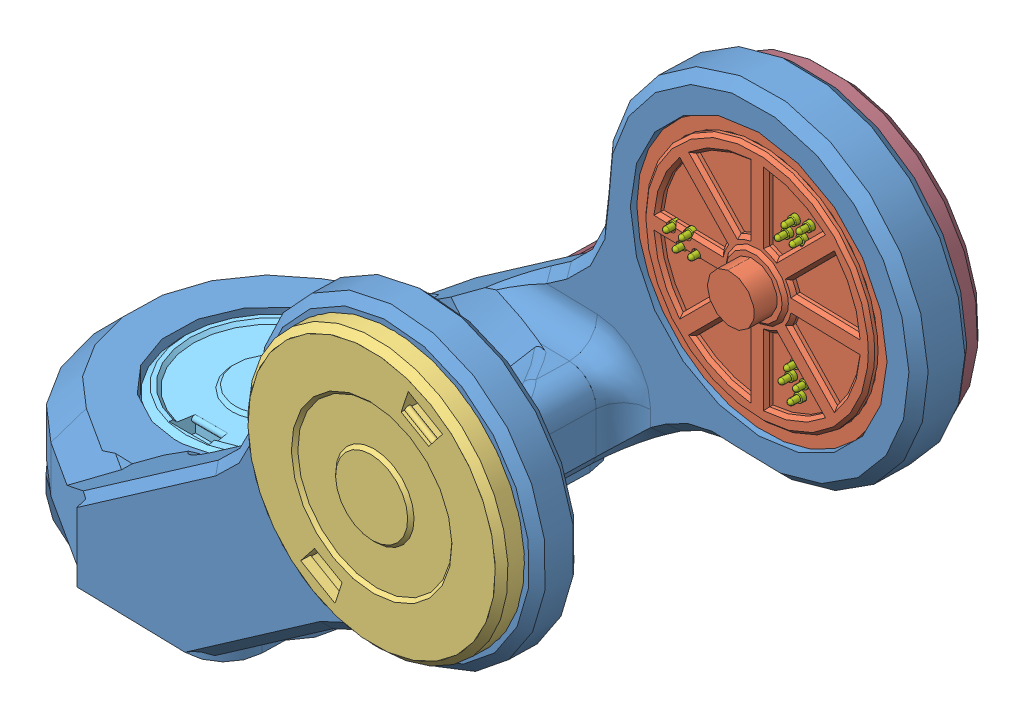
SolidWorks assembly fork_assembly_211201, configuration По умолчанию. Lengths in mm.
Overall size (216.2 166.88 147.03).
40 component instances, 13 part files, 37 mates.
Components (placement in the parent):
- main_fork_211124-1: main_fork_211124 [По умолчанию] at (-30.0243 -35 2.0927) x (0.99973 0 0.023253) z (-0.023253 0 0.99973) size (205.5 159 128)
- fixing_cup_211126-1: fixing_cup_211126 [По умолчанию] at (-28.7106 -35 -54.392) x (0.99973 0 0.023253) z (-0.023253 0 0.99973) size (90 90 26.5)
- fork_fixing_crew_211126-1: fork_fixing_crew_211126 [По умолчанию] at (-31.3381 -35 58.5774) x (0.878636 -0.477054 0.020436) z (-0.476925 -0.878874 -0.011093) size (83 13.97 83)
- fixing_ring_211126-2: fixing_ring_211126 [По умолчанию] at (-28.7106 -35 -54.392) x (0.922257 0.385983 0.021451) z (0.023253 0 -0.99973) size (90 90 5.02)
- main_fork_fixing_211201-1: main_fork_fixing_211201 [По умолчанию] at (-134.4961 -139 -0.3372) size (58 48 58)
- asm_contact_brd_211214-1: asm_contact_brd_211214 [По умолчанию] at (-28.7106 -35 -54.392) x (-0.573421 0.819152 -0.013337) z (-0.818931 -0.573576 -0.019047) size (65 12.3 65)
  - contact_brd3_211213-1: contact_brd3_211213 [По умолчанию] at origin size (65 1.5 65)
  - pogopin_a734_3_3x12_211214-5: pogopin_a734_3_3x12_211214 [По умолчанию] at (-24.5 -10.8 0) x (-0.957911 0 -0.287064) z (0 -1 0) size (3.3 3.3 12)
  - pogopin_a734_3_3x12_211214-6: pogopin_a734_3_3x12_211214 [По умолчанию] at (-19.5 -10.8 0) x (-0.957911 0 -0.287064) z (0 -1 0) size (3.3 3.3 12)
  - pogopin_a734_3_3x12_211214-7: pogopin_a734_3_3x12_211214 [По умолчанию] at (-27.2075 -10.8 4) x (-0.957911 0 -0.287064) z (0 -1 0) size (3.3 3.3 12)
  - pogopin_a734_3_3x12_211214-8: pogopin_a734_3_3x12_211214 [По умолчанию] at (-22.1416 -10.8 4) x (-0.957911 0 -0.287064) z (0 -1 0) size (3.3 3.3 12)
  - pogopin_a734_3_3x12_211214-9: pogopin_a734_3_3x12_211214 [По умолчанию] at (17.0679 -10.8 21.5624) x (0.230351 0 0.973108) z (0 -1 0) size (3.3 3.3 12)
  - pogopin_a734_3_3x12_211214-10: pogopin_a734_3_3x12_211214 [По умолчанию] at (10.1397 -10.8 -25.5624) x (0.72756 0 -0.686044) z (0 -1 0) size (3.3 3.3 12)
  - pogopin_a734_3_3x12_211214-11: pogopin_a734_3_3x12_211214 [По умолчанию] at (14.5349 -10.8 17.1752) x (0.230351 0 0.973108) z (0 -1 0) size (3.3 3.3 12)
  - pogopin_a734_3_3x12_211214-12: pogopin_a734_3_3x12_211214 [По умолчанию] at (7.6067 -10.8 -21.1752) x (0.72756 0 -0.686044) z (0 -1 0) size (3.3 3.3 12)
  - pogopin_a734_3_3x12_211214-13: pogopin_a734_3_3x12_211214 [По умолчанию] at (12.25 -10.8 21.2176) x (0.230351 0 0.973108) z (0 -1 0) size (3.3 3.3 12)
  - pogopin_a734_3_3x12_211214-14: pogopin_a734_3_3x12_211214 [По умолчанию] at (12.25 -10.8 -21.2176) x (0.72756 0 -0.686044) z (0 -1 0) size (3.3 3.3 12)
  - pogopin_a734_3_3x12_211214-15: pogopin_a734_3_3x12_211214 [По умолчанию] at (9.75 -10.8 16.8875) x (0.230351 0 0.973108) z (0 -1 0) size (3.3 3.3 12)
  - pogopin_a734_3_3x12_211214-16: pogopin_a734_3_3x12_211214 [По умолчанию] at (9.75 -10.8 -16.8875) x (0.72756 0 -0.686044) z (0 -1 0) size (3.3 3.3 12)
- asm_contact_brd4_211214-1: asm_contact_brd4_211214 [По умолчанию] at (-134.4961 -114.5 -0.3372) x (-0.99973 0 -0.023253) z (0.023253 0 -0.99973) size (92 17.38 113.16)
  - contact_brd4_211213-1: contact_brd4_211213 [По умолчанию] at origin size (92 1.5 105)
  - pogopin_a734_3_3x12_211214-1: pogopin_a734_3_3x12_211214 [По умолчанию] at (39.5125 -10.8 18.1937) x (0.802221 0 0.597027) z (0 -1 0) size (3.3 3.3 12)
  - pogopin_a734_3_3x12_211214-2: pogopin_a734_3_3x12_211214 [По умолчанию] at (35.0753 -10.8 20.2507) x (0.802221 0 0.597027) z (0 -1 0) size (3.3 3.3 12)
  - pogopin_a734_3_3x12_211214-3: pogopin_a734_3_3x12_211214 [По умолчанию] at (35.1615 -10.8 15.6817) x (0.802221 0 0.597027) z (0 -1 0) size (3.3 3.3 12)
  - pogopin_a734_3_3x12_211214-4: pogopin_a734_3_3x12_211214 [По умолчанию] at (30.7439 -10.8 17.75) x (0.802221 0 0.597027) z (0 -1 0) size (3.3 3.3 12)
  - pogopin_a734_3_3x12_211214-5: pogopin_a734_3_3x12_211214 [По умолчанию] at (-4 -10.8 -38.2916) x (0.802221 0 0.597027) z (0 -1 0) size (3.3 3.3 12)
  - pogopin_a734_3_3x12_211214-6: pogopin_a734_3_3x12_211214 [По умолчанию] at (-4 -10.8 -43.3157) x (0.802221 0 0.597027) z (0 -1 0) size (3.3 3.3 12)
  - pogopin_a734_3_3x12_211214-7: pogopin_a734_3_3x12_211214 [По умолчанию] at (0 -10.8 -40.5014) x (0.802221 0 0.597027) z (0 -1 0) size (3.3 3.3 12)
  - pogopin_a734_3_3x12_211214-8: pogopin_a734_3_3x12_211214 [По умолчанию] at (0 -10.8 -35.5) x (0.802221 0 0.597027) z (0 -1 0) size (3.3 3.3 12)
  - pogopin_a734_3_3x12_211214-9: pogopin_a734_3_3x12_211214 [По умолчанию] at (-31.1615 -10.8 22.6099) x (0.802221 0 0.597027) z (0 -1 0) size (3.3 3.3 12)
  - pogopin_a734_3_3x12_211214-10: pogopin_a734_3_3x12_211214 [По умолчанию] at (-35.5125 -10.8 25.122) x (0.802221 0 0.597027) z (0 -1 0) size (3.3 3.3 12)
  - pogopin_a734_3_3x12_211214-11: pogopin_a734_3_3x12_211214 [По умолчанию] at (-35.0753 -10.8 20.2507) x (0.802221 0 0.597027) z (0 -1 0) size (3.3 3.3 12)
  - pogopin_a734_3_3x12_211214-12: pogopin_a734_3_3x12_211214 [По умолчанию] at (-30.7439 -10.8 17.75) x (0.802221 0 0.597027) z (0 -1 0) size (3.3 3.3 12)
  - pld_8r_211215-1: pld_8r_211215 [По умолчанию] at (-2.417 -2.49 55.73) x (1 0 0) z (0 1 0) size (10.16 13.05 9.07)
- fork_board_fixer_211215-1: fork_board_fixer_211215 [По умолчанию] at (-134.4961 -123.5 -0.3372) x (0.99973 0 0.023253) z (-0.023253 0 0.99973) size (100 9 100)
- asm_com__211215-1: asm_com__211215 [По умолчанию] at (-90.4113 -78.5035 -69.8906) x (-0.573421 0.819152 -0.013337) z (0.818931 0.573576 0.019047) size (12.74 9.6 112.44)
  - conect_brd2_211214-1: conect_brd2_211214 [По умолчанию] at origin size (12.74 1.5 112.44)
  - pbd_8_211215-1: pbd_8_211215 [По умолчанию] at (0.133 -1.8298 56.5764) x (1 0 0) z (0 0 -1) size (10.23 9.1 5.08)
  - pbd_8_211215-2: pbd_8_211215 [По умолчанию] at (3.4585 -1.8298 -49.3785) x (0.587785 0 -0.809017) z (-0.809017 0 -0.587785) size (10.23 9.1 5.08)
- main_cap_211215-2: main_cap_211215 [По умолчанию] at (-28.5013 -35 -63.3896) x (-0.999729 -0.000909 -0.023252) z (0.000909 -1 0.000021) size (165.73 23 131)
Mates (geometry in assembly coordinates):
- Концентричный8: concentric anti-aligned: cylinder of main_fork_211124-1 through (-28.5943 -35 -59.3906) axis (-0.023253 0 0.99973) radius 46; cylinder of fork_fixing_crew_211126-1 through (-31.6404 -35 71.5739) axis (0.023253 0 -0.99973) radius 41.5
- Расстояние1: distance = 4 mm anti-aligned: plane of fork_fixing_crew_211126-1 through (-31.5706 -35 68.5747) normal (0.023253 0 -0.99973); plane of main_fork_211124-1 through (-31.4776 -35 64.5758) normal (-0.023253 0 0.99973)
- Совпадение13: coincident anti-aligned: plane of fixing_cup_211126-1 through (-28.7106 -35 -54.392) normal (0.023253 0 -0.99973); plane of fixing_ring_211126-2 through (-28.7106 -35 -54.392) normal (-0.023253 0 0.99973)
- Концентричный9: concentric aligned: cylinder of main_fork_211124-1 through (-29.1524 -35 -35.3971) axis (0.023253 0 -0.99973) radius 41; cylinder of fixing_cup_211126-1 through (-28.8617 -35 -47.8938) axis (0.023253 0 -0.99973) radius 40.5
- Совпадение15: coincident anti-aligned: plane of main_fork_211124-1 through (-43.888 7.2862 -63.7474) normal (0.939439 0.34202 0.02185); plane of fixing_cup_211126-1 through (-28.8617 -35 -47.8938) normal (-0.939439 -0.34202 -0.02185)
- Концентричный10: concentric aligned: cylinder of main_fork_211124-1 through (-28.5013 -35 -63.3896) axis (-0.023253 0 0.99973) radius 45; cylinder of fixing_ring_211126-2 through (-28.6059 -35 -58.8908) axis (-0.023253 0 0.99973) radius 45
- Совпадение21: coincident anti-aligned: plane of main_fork_211124-1 through (-134.4961 -99 -0.3372) normal (0 1 0); plane of main_fork_fixing_211201-1 through (-134.4961 -99 -0.3372) normal (0 -1 0)
- Концентричный13: concentric aligned: cylinder of main_fork_211124-1 through (-134.4961 -59 -0.3372) axis (0 -1 0) radius 30; cylinder of main_fork_fixing_211201-1 through (-134.4961 -92 -0.3372) axis (0 -1 0) radius 29
- Концентричный16: concentric anti-aligned: cylinder of main_fork_211124-1 through (-134.4961 -92 -0.3372) axis (0 1 0) radius 45.1398; cylinder of contact_brd4_211213-1 through (-134.4961 -90.5 -0.3372) axis (0 -1 0) radius 46
- Совпадение23: coincident anti-aligned: plane of main_fork_211124-1 through (-134.4961 -92 -0.3372) normal (0 1 0); plane of contact_brd4_211213-1 through (-134.4961 -92 -0.3372) normal (0 -1 0)
- Концентричный17: concentric aligned: cylinder of fixing_cup_211126-1 through (-56.5394 -33.3865 -38.5348) axis (0.023253 0 -0.99973) radius 1.45; cylinder of asm_contact_brd_211214-1/pogopin_a734_3_3x12_211214-1 through (-54.3652 -33.3865 -132.0165) axis (0.023253 0 -0.99973) radius 1.35
- Концентричный18: concentric aligned: cylinder of fixing_cup_211126-1 through (-16.7686 -59.5814 -37.6098) axis (0.023253 0 -0.99973) radius 1.45; cylinder of asm_contact_brd_211214-1/pogopin_a734_3_3x12_211214-7 through (-16.357 -59.5814 -55.305) axis (0.023253 0 -0.99973) radius 1.35
- Концентричный19: concentric aligned: cylinder of fixing_cup_211126-1 through (-17.9125 -50.9735 -37.6364) axis (0.023253 0 -0.99973) radius 1.45; cylinder of asm_contact_brd_211214-1/pogopin_a734_3_3x12_211214-6 through (-17.5009 -50.9735 -55.3316) axis (0.023253 0 -0.99973) radius 1.35
- Совпадение26: coincident anti-aligned: plane of main_fork_211124-1 through (-28.8268 -35 -49.3933) normal (0.023253 0 -0.99973); plane of fixing_cup_211126-1 through (-28.8268 -35 -49.3933) normal (-0.023253 0 0.99973)
- Концентричный20: concentric aligned: cylinder of asm_contact_brd_211214-1/contact_brd3_211213-1 through (-52.9436 -47.4055 -56.456) axis (-0.023253 0 0.99973) radius 0.5; cylinder of conect_brd_211213-1 through (-52.6529 -47.4055 -68.9527) axis (-0.023253 0 0.99973) radius 0.5
- Концентричный21: concentric aligned: cylinder of asm_contact_brd_211214-1/contact_brd3_211213-1 through (-50.8635 -45.9486 -56.4077) axis (-0.023253 0 0.99973) radius 0.5; cylinder of conect_brd_211213-1 through (-50.5729 -45.9486 -68.9043) axis (-0.023253 0 0.99973) radius 0.5
- Расстояние2: distance = 10 mm anti-aligned: plane of asm_contact_brd_211214-1/contact_brd3_211213-1 through (-28.6757 -35 -55.8916) normal (0.023253 0 -0.99973); plane of conect_brd_211213-1 through (-90.1885 -78.322 -68.3253) normal (-0.023253 0 0.99973)
- Концентричный22: concentric anti-aligned: cylinder of asm_contact_brd_211214-1/contact_brd3_211213-1 through (-50.8635 -45.9486 -56.4077) axis (-0.023253 0 0.99973) radius 0.5; cylinder of conect_brd2_211214-1 through (-50.6077 -45.9486 -67.4047) axis (0.023253 0 -0.99973) radius 0.5
- Концентричный23: concentric anti-aligned: cylinder of asm_contact_brd_211214-1/contact_brd3_211213-1 through (-46.494 -52.1906 -56.306) axis (-0.023253 0 0.99973) radius 0.5; cylinder of conect_brd2_211214-1 through (-46.2383 -52.1906 -67.3031) axis (0.023253 0 -0.99973) radius 0.5
- Расстояние3: distance = 10 mm anti-aligned: plane of asm_contact_brd_211214-1/contact_brd3_211213-1 through (-28.6757 -35 -55.8916) normal (0.023253 0 -0.99973); plane of conect_brd2_211214-1 through (-90.4476 -78.5035 -68.3313) normal (-0.023253 0 0.99973)
- Параллельность4: parallel anti-aligned: plane of contact_brd4_211213-1 through (-129.939 -90.5 -67.2493) normal (0.023253 0 -0.99973); plane of conect_brd2_211214-1 through (-90.4476 -78.5035 -68.3313) normal (-0.023253 0 0.99973)
- Параллельность5: parallel anti-aligned: plane of conect_brd2_211214-1 through (-90.4476 -78.5035 -68.3313) normal (-0.023253 0 0.99973); plane of asm_contact_brd4_211214-1/contact_brd4_211213-1 through (-127.1258 -113 -59.1817) normal (0.023253 0 -0.99973)
- Концентричный25: concentric aligned: cylinder of asm_contact_brd4_211214-1/pogopin_a734_3_3x12_211214-12 through (-103.3478 -113.3 -17.3675) axis (0 1 0) radius 1.35; cylinder of fork_board_fixer_211215-1 through (-103.3478 -123.5 -17.3675) axis (0 1 0) radius 1.4
- Концентричный26: concentric aligned: cylinder of asm_contact_brd4_211214-1/pogopin_a734_3_3x12_211214-1 through (-173.5748 -113.3 -19.4448) axis (0 1 0) radius 1.35; cylinder of fork_board_fixer_211215-1 through (-173.5748 -123.5 -19.4448) axis (0 1 0) radius 1.4
- Концентричный28: concentric anti-aligned: cylinder of main_fork_211124-1 through (-134.4961 -125.5 -0.3372) axis (0 1 0) radius 33; cylinder of asm_contact_brd4_211214-1/contact_brd4_211213-1 through (-134.4961 -113 -0.3372) axis (0 -1 0) radius 46
- Совпадение33: coincident anti-aligned: plane of main_fork_211124-1 through (-134.4961 -113 -0.3372) normal (0 -1 0); plane of asm_contact_brd4_211214-1/contact_brd4_211213-1 through (-134.4961 -113 -0.3372) normal (0 1 0)
- Совпадение35: coincident anti-aligned: plane of main_fork_211124-1 through (-134.4961 -114.5 -0.3372) normal (0 -1 0); plane of fork_board_fixer_211215-1 through (-134.4961 -114.5 -0.3372) normal (0 1 0)
- Совпадение36: coincident anti-aligned: plane of fixing_cup_211126-1 through (-28.7106 -35 -54.392) normal (0.023253 0 -0.99973); plane of asm_contact_brd_211214-1/contact_brd3_211213-1 through (-28.7106 -35 -54.392) normal (-0.023253 0 0.99973)
- Совпадение37: coincident anti-aligned: plane of conect_brd2_211214-1 through (-90.4476 -78.5035 -68.3313) normal (-0.023253 0 0.99973); plane of pbd_8_211215-1 through (-132.7356 -116.99 -69.3149) normal (0.023253 0 -0.99973)
- Совпадение38: coincident aligned: plane of asm_contact_brd4_211214-1/pld_8r_211215-1 through (-138.203 -113 -58.999) normal (-0.99973 0 -0.023253); plane of pbd_8_211215-1 through (-138.1463 -113 -61.4386) normal (-0.99973 0 -0.023253)
- Совпадение39: coincident aligned: plane of asm_contact_brd4_211214-1/pld_8r_211215-1 through (-138.203 -107.92 -58.999) normal (0 1 0); plane of pbd_8_211215-1 through (-138.1463 -107.92 -61.4386) normal (0 1 0)
- Концентричный29: concentric anti-aligned: cylinder of asm_contact_brd_211214-1/contact_brd3_211213-1 through (-50.8635 -45.9486 -56.4077) axis (-0.023253 0 0.99973) radius 0.5; cylinder of asm_com__211215-1/conect_brd2_211214-1 through (-50.6064 -45.9486 -67.4644) axis (0.023253 0 -0.99973) radius 0.5
- Концентричный30: concentric anti-aligned: cylinder of asm_contact_brd_211214-1/contact_brd3_211213-1 through (-52.9436 -47.4055 -56.456) axis (-0.023253 0 0.99973) radius 0.5; cylinder of asm_com__211215-1/conect_brd2_211214-1 through (-52.6864 -47.4055 -67.5128) axis (0.023253 0 -0.99973) radius 0.5
- Совпадение40: coincident anti-aligned: plane of asm_contact_brd4_211214-1/pld_8r_211215-1 through (-130.66 -116.99 -61.3242) normal (0.023253 0 -0.99973); plane of asm_com__211215-1/pbd_8_211215-2 through (-133.053 -103.9928 -61.3799) normal (-0.023253 0 0.99973)
- Совпадение43: coincident anti-aligned: plane of main_fork_211124-1 through (-28.5013 -35 -63.3896) normal (0.023253 0 -0.99973); plane of main_cap_211215-2 through (-28.5013 -35 -63.3896) normal (-0.023253 0 0.99973)
- Концентричный32: concentric aligned: cylinder of fixing_cup_211126-1 through (-28.478 -35 -64.3893) axis (-0.023253 0 0.99973) radius 16.85; cylinder of main_cap_211215-2 through (-28.3618 -35 -69.3879) axis (-0.023253 0 0.99973) radius 38.9538
- Параллельность8: parallel aligned: plane of main_fork_211124-1 through (-36.5127 -23.752 -59.5748) normal (-0.575593 0.817627 -0.013388); plane of main_cap_211215-2 through (-156.5455 -114.1164 -62.3666) normal (-0.575593 0.817627 -0.013388)
